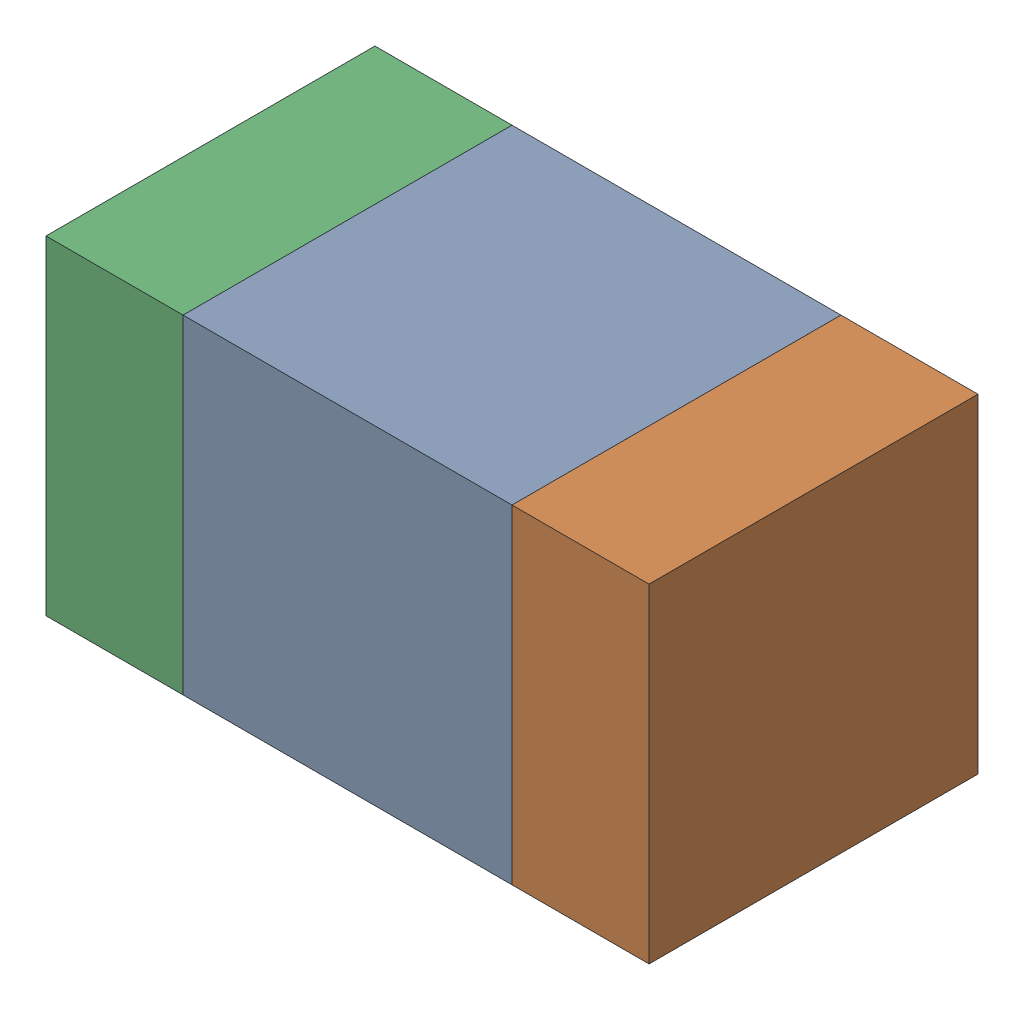
SolidWorks assembly C400PCB, configuration Default. Lengths in mm.
Overall size (1.1 0.6 0.6).
6 component instances, 2 part files, 0 mates.
Components (placement in the parent):
- 761606048-1: 761606048 [Default] at (127.2 100.6 0) size (0.6 0.6 0.6)
  - Extruded_9-1: Extruded_9 [Default] at origin size (0.6 0.6 0.6)
- 854785160-1: 854785160 [Default] at (127.625 100.6 0) size (0.25 0.6 0.6)
  - Extruded_19-1: Extruded_19 [Default] at origin size (0.25 0.6 0.6)
- 854785160-2: 854785160 [Default] at (126.775 100.6 0) size (0.25 0.6 0.6)
  - Extruded_19-1: Extruded_19 [Default] at origin size (0.25 0.6 0.6)
